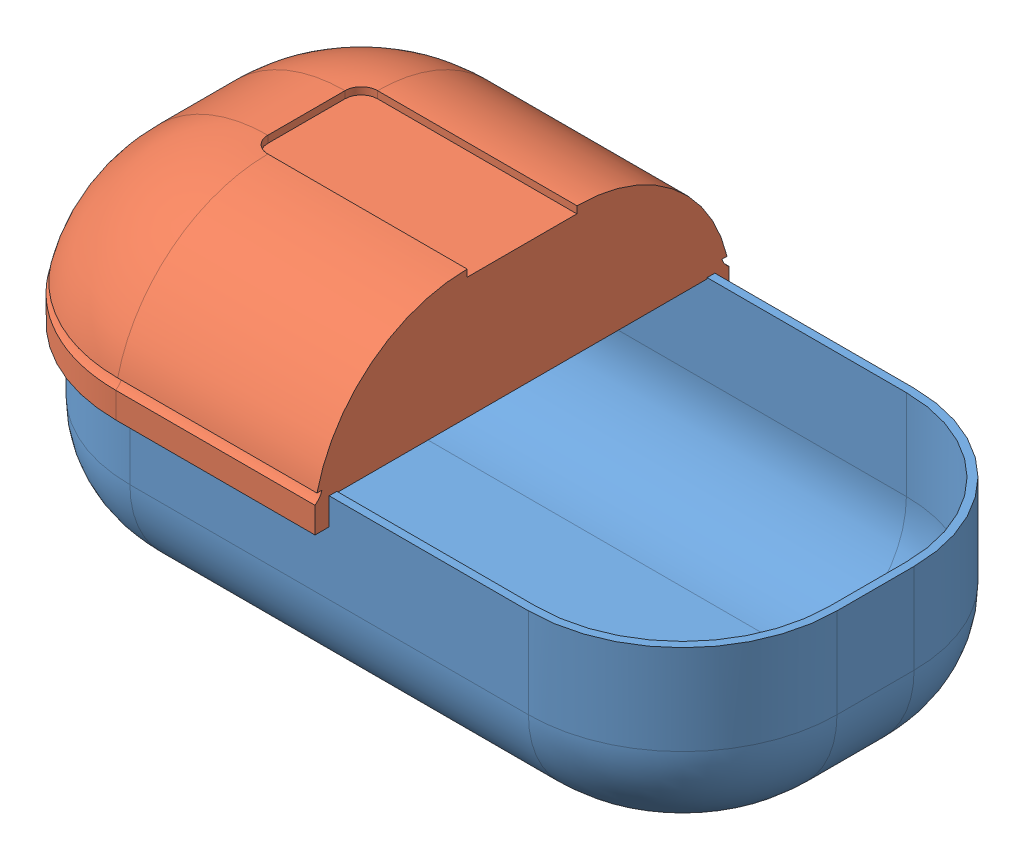
SolidWorks assembly Ensamblaje1, configuration Predeterminado. Lengths in mm.
Overall size (561 249.09 322).
2 component instances, 2 part files, 2 mates.
Components (placement in the parent):
- base-1: base [Predeterminado] at (-36.5493 52.5156 0) size (550 150 300)
- tapa-1: tapa [Predeterminado] at (-36.5493 51.6041 0) size (286 120 322)
Mates (geometry in assembly coordinates):
- Coincidente3: coincident aligned: plane of base-1 through (-36.5493 52.5156 0) normal (1 0 0); plane of tapa-1 through (-36.5493 51.6041 0) normal (1 0 0)
- Coincidente4: coincident aligned: plane of base-1 through (-36.5493 52.5156 0) normal (0 0 1); plane of tapa-1 through (-36.5493 51.6041 0) normal (0 0 1)
